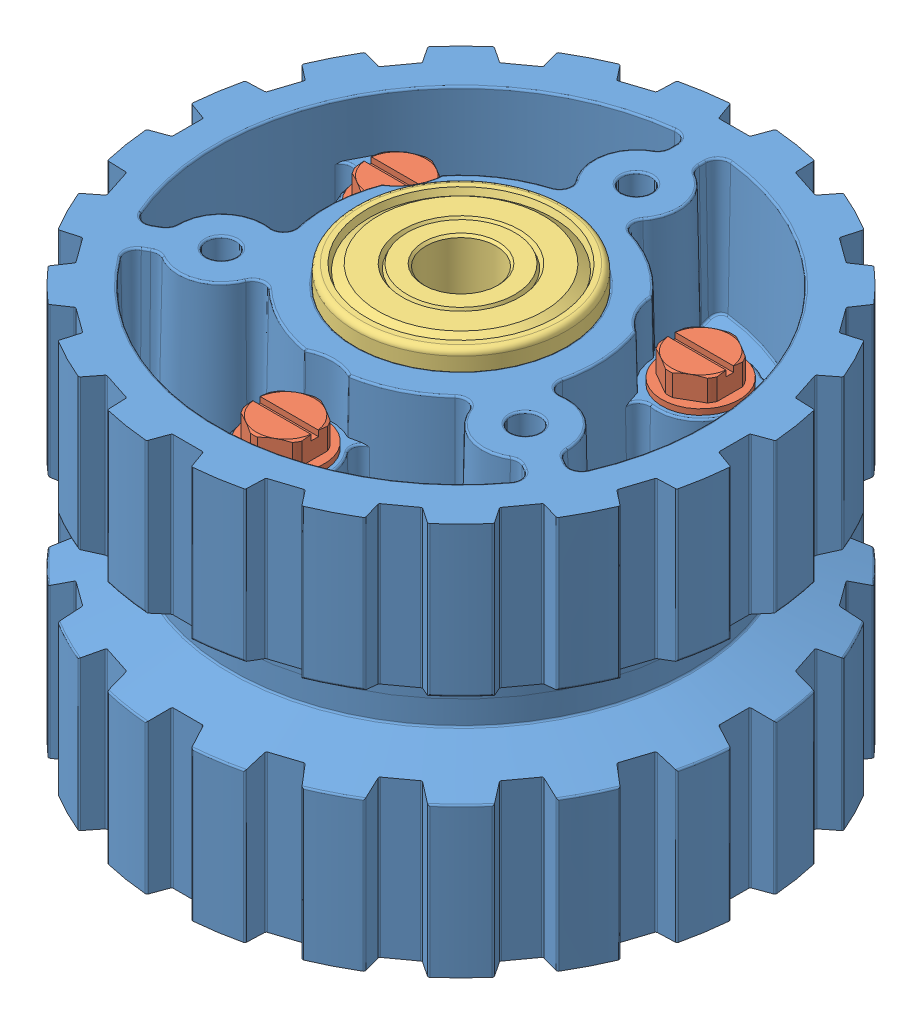
SolidWorks assembly 20T pulley back to back, configuration Default. Lengths in mm.
Overall size (79.28 58.42 79.28).
10 component instances, 3 part files, 0 mates.
Components (placement in the parent):
- am-3298 20 tooth Molded Tank Pulley Half r3-1: am-3298 20 tooth Molded Tank Pulley Half r3 [Default] at (-66.929 10.7589 19.6249) size (79.28 27.95 79.28)
- am-3298 20 tooth Molded Tank Pulley Half r3-2: am-3298 20 tooth Molded Tank Pulley Half r3 [Default] at (-66.929 10.7589 19.6249) x (1 0 0) z (0 0 -1) size (79.28 27.95 79.28)
- 10-24 Hex Washer Rolling x 1.25_93882A213-1: 10-24 Hex Washer Rolling x 1.25_93882A213 [Default] at (-46.3067 30.1899 7.7187) x (1 0 0) z (0 1 0) size (10.52 10.52 35.59)
- 10-24 Hex Washer Rolling x 1.25_93882A213-2: 10-24 Hex Washer Rolling x 1.25_93882A213 [Default] at (-87.5512 30.1899 7.7187) x (1 0 0) z (0 1 0) size (10.52 10.52 35.59)
- 10-24 Hex Washer Rolling x 1.25_93882A213-3: 10-24 Hex Washer Rolling x 1.25_93882A213 [Default] at (-66.929 30.1899 43.4374) x (1 0 0) z (0 1 0) size (10.52 10.52 35.59)
- 10-24 Hex Washer Rolling x 1.25_93882A213-4: 10-24 Hex Washer Rolling x 1.25_93882A213 [Default] at (-66.929 -8.6721 -4.1876) x (-0.837169 0 -0.546944) z (0 -1 0) size (10.52 10.52 35.59)
- 10-24 Hex Washer Rolling x 1.25_93882A213-5: 10-24 Hex Washer Rolling x 1.25_93882A213 [Default] at (-87.5512 -8.6721 31.5312) x (-0.837169 0 -0.546944) z (0 -1 0) size (10.52 10.52 35.59)
- 10-24 Hex Washer Rolling x 1.25_93882A213-6: 10-24 Hex Washer Rolling x 1.25_93882A213 [Default] at (-46.3067 -8.6721 31.5312) x (-0.837169 0 -0.546944) z (0 -1 0) size (10.52 10.52 35.59)
- 1614Z Bearing-1: 1614Z Bearing [Default] at (-66.929 -13.6886 19.6249) x (1 0 0) z (0 1 0) size (28.58 28.58 9.53)
- 1614Z Bearing-2: 1614Z Bearing [Default] at (-66.929 35.2064 19.6249) x (1 0 0) z (0 -1 0) size (28.58 28.58 9.53)
